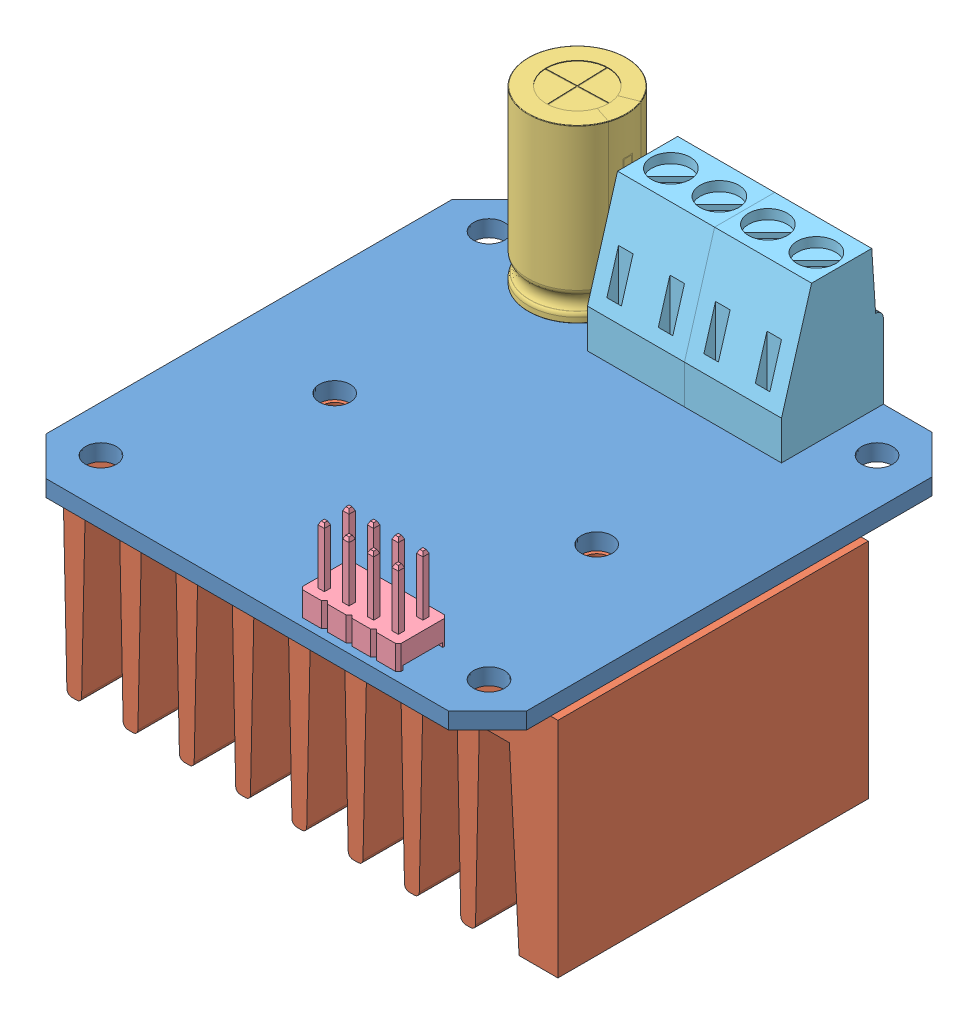
SolidWorks assembly BTS7960 43A HIGH POWER H BRIDGE MODULE, configuration Default. Lengths in mm.
Overall size (51 42.4 49.96).
6 component instances, 5 part files, 21 mates.
Components (placement in the parent):
- PCB, BTS7960 43A HIGH POWER H BRIDGE MODULE-1: PCB, BTS7960 43A HIGH POWER H BRIDGE MODULE [Default] at origin size (49.5 1.7 49.8)
- HEATSINK, BTS7960 43A HIGH POWER H BRIDGE MODULE-1: HEATSINK, BTS7960 43A HIGH POWER H BRIDGE MODULE [Default] at (0 0 2.4) size (51 23 32.02)
- ALUMINUM ELECTROLYTIC CAPACITOR, 330 uF, BTS7960 43A HIGH POWER H BRIDGE MODULE-1: ALUMINUM ELECTROLYTIC CAPACITOR, 330 uF, BTS7960 43A HIGH POWER H BRIDGE MODULE [Default] at (-10.75 1.8 -19.85) x (0.999469 0 -0.032584) z (0.032584 0 0.999469) size (10.1 18.7 10.1)
- 8 PIN HEADER, IC, BTS7960 43A HIGH POWER H BRIDGE MODULE-1: 8 PIN HEADER, IC, BTS7960 43A HIGH POWER H BRIDGE MODULE [Default] at (-34.78 4.2 20.29) x (0 0 -1) z (-1 0 0) size (5.08 11.6 10.16)
- EUROSTYLE TERMINAL BLOCK 2 POS 5.0 MM RA PLUG, BTS7960 43A HIGH POWER H BRIDGE MODULE-1: EUROSTYLE TERMINAL BLOCK 2 POS 5.0 MM RA PLUG, BTS7960 43A HIGH POWER H BRIDGE MODULE [Default] at (0.75 4.2 -6.5) size (10 14.5 10.5)
- EUROSTYLE TERMINAL BLOCK 2 POS 5.0 MM RA PLUG, BTS7960 43A HIGH POWER H BRIDGE MODULE-2: EUROSTYLE TERMINAL BLOCK 2 POS 5.0 MM RA PLUG, BTS7960 43A HIGH POWER H BRIDGE MODULE [Default] at (10.75 4.2 -6.5) size (10 14.5 10.5)
Mates (geometry in assembly coordinates):
- Coincident1: coordinate: point of PCB, BTS7960 43A HIGH POWER H BRIDGE MODULE-1
- Coincident2: coincident anti-aligned: plane of PCB, BTS7960 43A HIGH POWER H BRIDGE MODULE-1 through (0 0 0) normal (0 -1 0); plane of HEATSINK, BTS7960 43A HIGH POWER H BRIDGE MODULE-1 through (0 0 2.4) normal (0 1 0)
- Distance1: distance = 6.5 mm aligned: plane of HEATSINK, BTS7960 43A HIGH POWER H BRIDGE MODULE-1 through (-25.5 -4.5 18.4) normal (0 0 1); plane of PCB, BTS7960 43A HIGH POWER H BRIDGE MODULE-1 through (-24.75 1.7 24.9) normal (0 0 1)
- Coincident4: coincident anti-aligned: plane of PCB, BTS7960 43A HIGH POWER H BRIDGE MODULE-1 through (0 1.7 0) normal (0 1 0); plane of ALUMINUM ELECTROLYTIC CAPACITOR, 330 uF, BTS7960 43A HIGH POWER H BRIDGE MODULE-1 through (-10.75 1.7 -19.85) normal (0 -1 0)
- Distance2: distance = 14 mm: line of ALUMINUM ELECTROLYTIC CAPACITOR, 330 uF, BTS7960 43A HIGH POWER H BRIDGE MODULE-1 through (-10.75 4.6983 -19.85) axis (0 1 0); plane of PCB, BTS7960 43A HIGH POWER H BRIDGE MODULE-1 through (-24.75 1.7 -24.9) normal (-1 0 0)
- Tangent1: tangent aligned: cylinder of ALUMINUM ELECTROLYTIC CAPACITOR, 330 uF, BTS7960 43A HIGH POWER H BRIDGE MODULE-1 through (-10.75 4.7 -19.85) axis (0 1 0) radius 5.05; plane of PCB, BTS7960 43A HIGH POWER H BRIDGE MODULE-1 through (-24.75 1.7 -24.9) normal (0 0 -1)
- Coincident5: coincident anti-aligned: plane of PCB, BTS7960 43A HIGH POWER H BRIDGE MODULE-1 through (0 1.7 0) normal (0 1 0); plane of BTN7960 IC, BTS7960 43A HIGH POWER H BRIDGE MODULE-1 through (1.15 1.7 -2.8) normal (0 -1 0)
- Coincident6: coincident aligned: plane of HEATSINK, BTS7960 43A HIGH POWER H BRIDGE MODULE-1 through (0 0 2.4) normal (1 0 0)
- Distance4: distance = 14 mm aligned: plane of BTN7960 IC, BTS7960 43A HIGH POWER H BRIDGE MODULE-1 through (10.75 1.7 1.8) normal (1 0 0); plane of PCB, BTS7960 43A HIGH POWER H BRIDGE MODULE-1 through (24.75 1.7 -24.9) normal (1 0 0)
- Coincident7: coincident anti-aligned: plane of PCB, BTS7960 43A HIGH POWER H BRIDGE MODULE-1 through (0 1.7 0) normal (0 1 0); plane of NXP 74HC244D, BUFFER AND LINE DRIVER, BTS7960 43A HIGH POWER H BRIDGE MODULE-1 through (17.35 1.7 12.1) normal (0 -1 0)
- Distance5: distance = 0.9 mm: plane of PCB, BTS7960 43A HIGH POWER H BRIDGE MODULE-1 through (24.75 1.7 -24.9) normal (1 0 0); line of NXP 74HC244D, BUFFER AND LINE DRIVER, BTS7960 43A HIGH POWER H BRIDGE MODULE-1 through (23.85 3 15.9) axis (0 0 -1)
- Distance6: distance = 9 mm: plane of PCB, BTS7960 43A HIGH POWER H BRIDGE MODULE-1 through (-24.75 1.7 24.9) normal (0 0 1); line of NXP 74HC244D, BUFFER AND LINE DRIVER, BTS7960 43A HIGH POWER H BRIDGE MODULE-1 through (10.85 3 15.9) axis (1 0 0)
- Coincident8: coincident anti-aligned: plane of PCB, BTS7960 43A HIGH POWER H BRIDGE MODULE-1 through (0 1.7 0) normal (0 1 0); plane of 8 PIN HEADER, IC, BTS7960 43A HIGH POWER H BRIDGE MODULE-1 through (-34.78 1.7 22.53) normal (0 -1 0)
- Distance7: distance = 0.8 mm aligned: plane of 8 PIN HEADER, IC, BTS7960 43A HIGH POWER H BRIDGE MODULE-1 through (12.51 1.7 24.1) normal (0 0 1); plane of PCB, BTS7960 43A HIGH POWER H BRIDGE MODULE-1 through (-24.75 1.7 24.9) normal (0 0 1)
- Distance8: distance = 10 mm aligned: plane of 8 PIN HEADER, IC, BTS7960 43A HIGH POWER H BRIDGE MODULE-1 through (14.75 1.7 23.8) normal (1 0 0); plane of PCB, BTS7960 43A HIGH POWER H BRIDGE MODULE-1 through (24.75 1.7 -24.9) normal (1 0 0)
- Coincident9: coincident anti-aligned: plane of EUROSTYLE TERMINAL BLOCK 2 POS 5.0 MM RA PLUG, BTS7960 43A HIGH POWER H BRIDGE MODULE-1 through (5.75 4.2 -6.5) normal (1 0 0); plane of EUROSTYLE TERMINAL BLOCK 2 POS 5.0 MM RA PLUG, BTS7960 43A HIGH POWER H BRIDGE MODULE-2 through (5.75 4.2 -6.5) normal (-1 0 0)
- Coincident10: coincident aligned: plane of EUROSTYLE TERMINAL BLOCK 2 POS 5.0 MM RA PLUG, BTS7960 43A HIGH POWER H BRIDGE MODULE-1 through (-4.25 16.2 -24.3) normal (0 1 0); plane of EUROSTYLE TERMINAL BLOCK 2 POS 5.0 MM RA PLUG, BTS7960 43A HIGH POWER H BRIDGE MODULE-2 through (5.75 16.2 -24.3) normal (0 1 0)
- Coincident11: coincident aligned: plane of EUROSTYLE TERMINAL BLOCK 2 POS 5.0 MM RA PLUG, BTS7960 43A HIGH POWER H BRIDGE MODULE-1 through (20.7146 5.7 -14.4) normal (0 0 1); plane of EUROSTYLE TERMINAL BLOCK 2 POS 5.0 MM RA PLUG, BTS7960 43A HIGH POWER H BRIDGE MODULE-2 through (30.7146 5.7 -14.4) normal (0 0 1)
- Coincident12: coincident anti-aligned: plane of PCB, BTS7960 43A HIGH POWER H BRIDGE MODULE-1 through (0 1.7 0) normal (0 1 0); plane of EUROSTYLE TERMINAL BLOCK 2 POS 5.0 MM RA PLUG, BTS7960 43A HIGH POWER H BRIDGE MODULE-2 through (10.75 1.7 -6.5) normal (0 -1 0)
- Coincident13: coincident aligned: plane of PCB, BTS7960 43A HIGH POWER H BRIDGE MODULE-1 through (-24.75 1.7 -24.9) normal (0 0 -1); plane of EUROSTYLE TERMINAL BLOCK 2 POS 5.0 MM RA PLUG, BTS7960 43A HIGH POWER H BRIDGE MODULE-2 through (5.75 0.7 -24.9) normal (0 0 -1)
- Distance10: distance = 9 mm aligned: plane of EUROSTYLE TERMINAL BLOCK 2 POS 5.0 MM RA PLUG, BTS7960 43A HIGH POWER H BRIDGE MODULE-2 through (15.75 4.2 -6.5) normal (1 0 0); plane of PCB, BTS7960 43A HIGH POWER H BRIDGE MODULE-1 through (24.75 1.7 -24.9) normal (1 0 0)
